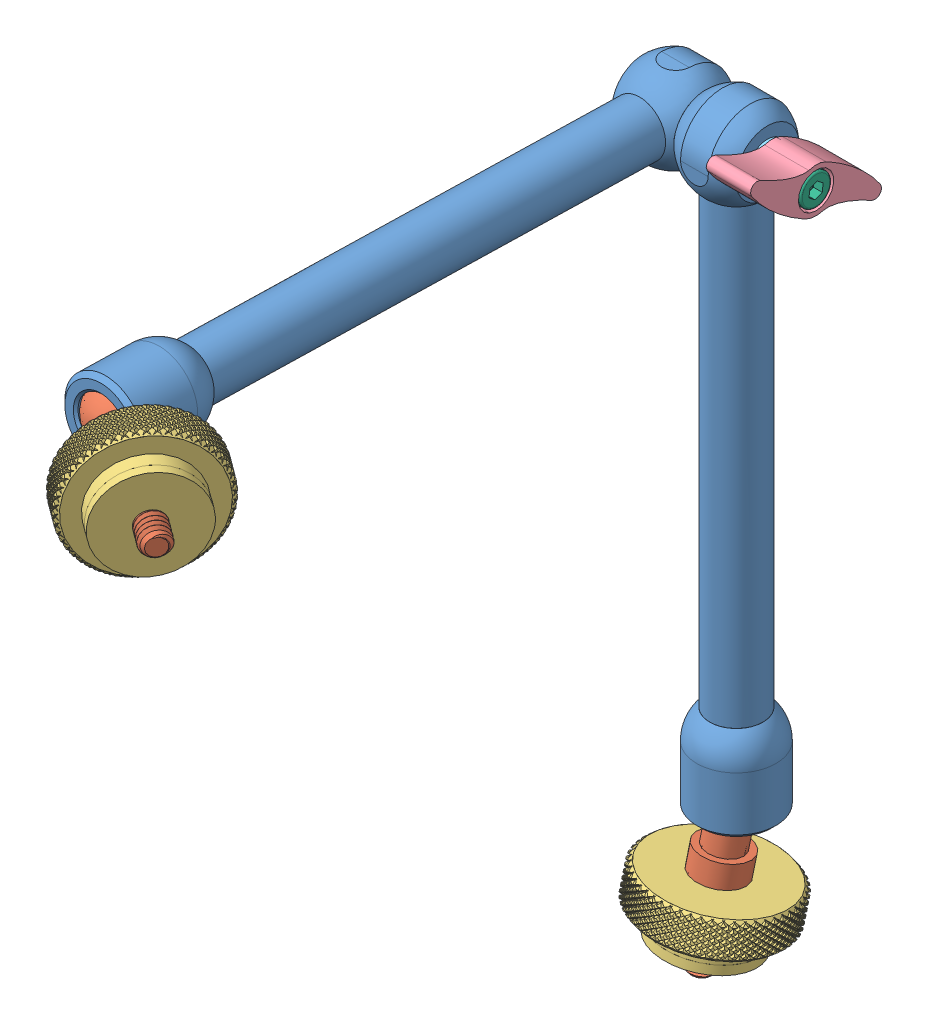
SolidWorks assembly Сборка5, configuration По умолчанию. Lengths in mm.
Overall size (43.73 180.2 172.08).
9 component instances, 6 part files, 14 mates.
Components (placement in the parent):
- kamerar_arm_leg-1: kamerar_arm_leg [По умолчанию] at (-34.7457 75.2471 19.6273) size (17.87 139.25 19)
- kamerar_arm_leg-2: kamerar_arm_leg [По умолчанию] at (-48.7457 75.2471 19.6273) x (-1 0 0) z (0 -0.999708 0.024164) size (17.87 139.25 19)
- kamerar_arm_screw-1: kamerar_arm_screw [По умолчанию] at (-34.7457 -49.6164 19.6273) x (-0.0774 -0.98469 0.156187) z (-0.3311 0.173153 0.927573) size (42.92 13.5 13.5)
- kamerar_arm_screw-2: kamerar_arm_screw [По умолчанию] at (-48.7457 78.2642 144.4543) x (0.807917 -0.035022 0.588254) z (-0.588093 0.015824 0.808638) size (42.92 13.5 13.5)
- kamerar_arm_thumb-1: kamerar_arm_thumb [По умолчанию] at (-36.6807 -74.2336 23.532) x (0.9929 -0.090322 -0.0774) z (0.0774 0.98469 -0.156187) size (30.01 30.01 13)
- kamerar_arm_thumb-2: kamerar_arm_thumb [По умолчанию] at (-28.5478 77.3887 159.1607) x (-0.585275 0.06872 0.807917) z (-0.807917 0.035022 -0.588254) size (30.01 30.01 13)
- kamerar_arm_thumb_screw-1: kamerar_arm_thumb_screw [По умолчанию] at (-26.7457 75.2471 19.6273) x (0 -0.461474 -0.887154) z (1 0 0) size (33 10.04 10)
- kamerar_arm_shtift-1: kamerar_arm_shtift [По умолчанию] at (-56.7457 75.2471 19.6273) x (0 -0.058831 -0.998268) z (1 0 0) size (10.2 10.2 31.5)
- socket head cap screw_din-1: socket head cap screw_din [DIN 912 M4 x 6 --- 6N] at (-16.7457 75.2471 19.6273) x (-1 0 0) z (0 0.924225 0.381849) size (10 7 7)
Mates (geometry in assembly coordinates):
- Совпадение1: coincident anti-aligned: plane of kamerar_arm_leg-1 through (-41.7457 65.2471 12.4859) normal (-1 0 0); plane of kamerar_arm_leg-2 through (-41.7457 82.628 29.4518) normal (1 0 0)
- Концентричный1: concentric anti-aligned: cylinder of kamerar_arm_leg-1 through (-25.8129 75.2471 19.6273) axis (-1 0 0) radius 4.5; cylinder of kamerar_arm_leg-2 through (-57.6785 75.2471 19.6273) axis (1 0 0) radius 4.5
- Концентричный2: concentric: sphere of kamerar_arm_leg-1; sphere of kamerar_arm_screw-1
- Концентричный3: concentric: sphere of kamerar_arm_leg-2; sphere of kamerar_arm_screw-2
- Концентричный4: concentric anti-aligned: cylinder of kamerar_arm_screw-1 through (-36.0615 -66.3561 22.2825) axis (0.0774 0.98469 -0.156187) radius 5.5; cylinder of kamerar_arm_thumb-1 through (-36.0615 -66.3561 22.2825) axis (-0.0774 -0.98469 0.156187) radius 3
- Совпадение2: coincident anti-aligned: plane of kamerar_arm_screw-1 through (-36.0615 -66.3561 22.2825) normal (-0.0774 -0.98469 0.156187); plane of kamerar_arm_thumb-1 through (-36.0615 -66.3561 22.2825) normal (0.0774 0.98469 -0.156187)
- Концентричный5: concentric anti-aligned: cylinder of kamerar_arm_screw-2 through (-35.0111 77.6689 154.4546) axis (-0.807917 0.035022 -0.588254) radius 5.5; cylinder of kamerar_arm_thumb-2 through (-35.0111 77.6689 154.4546) axis (0.807917 -0.035022 0.588254) radius 3
- Совпадение3: coincident anti-aligned: plane of kamerar_arm_screw-2 through (-35.0111 77.6689 154.4546) normal (0.807917 -0.035022 0.588254); plane of kamerar_arm_thumb-2 through (-35.0111 77.6689 154.4546) normal (-0.807917 0.035022 -0.588254)
- Концентричный6: concentric anti-aligned: cylinder of kamerar_arm_leg-1 through (-25.8129 75.2471 19.6273) axis (-1 0 0) radius 4.5; cylinder of kamerar_arm_thumb_screw-1 through (-16.7457 75.2471 19.6273) axis (1 0 0) radius 2.25
- Расстояние1: distance = 1 mm anti-aligned: plane of kamerar_arm_leg-1 through (-27.7457 65.2471 12.4859) normal (1 0 0); plane of kamerar_arm_thumb_screw-1 through (-26.7457 74.65 27.8071) normal (-1 0 0)
- Концентричный7: concentric anti-aligned: cylinder of kamerar_arm_leg-2 through (-57.6785 75.2471 19.6273) axis (1 0 0) radius 4.5; cylinder of kamerar_arm_shtift-1 through (-25.7457 75.2471 19.6273) axis (-1 0 0) radius 4.5
- Совпадение5: coincident anti-aligned: plane of kamerar_arm_leg-2 through (-55.7457 82.628 29.4518) normal (-1 0 0); plane of kamerar_arm_shtift-1 through (-55.7457 75.2471 19.6273) normal (1 0 0)
- Концентричный8: concentric aligned: cylinder of kamerar_arm_thumb_screw-1 through (-16.7457 75.2471 19.6273) axis (1 0 0) radius 2.25; cylinder of socket head cap screw_din-1 through (15.0043 75.2471 19.6273) axis (1 0 0) radius 3.5
- Совпадение6: coincident anti-aligned: plane of kamerar_arm_thumb_screw-1 through (-20.7457 74.2087 17.6312) normal (1 0 0); plane of socket head cap screw_din-1 through (-20.7457 73.9106 22.8621) normal (-1 0 0)
